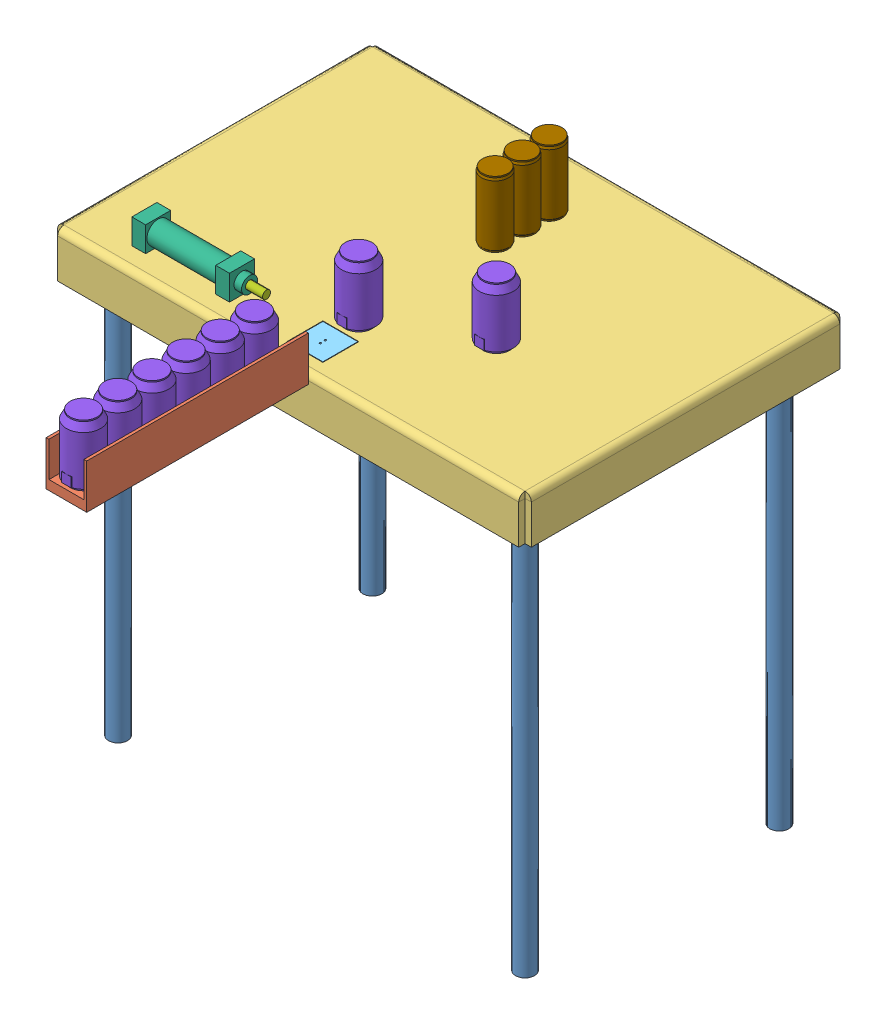
SolidWorks assembly Full_Assembly_v4, configuration Default. Lengths in mm.
Overall size (946.15 1065.21 1084.08).
19 component instances, 9 part files, 57 mates.
Components (placement in the parent):
- M37 Metal Table-1: M37 Metal Table [Default] at (-122.75 340.8931 1031.9817) size (914.4 863.6 609.6)
- Goose Output-1: Goose Output [Default] at (293.9688 417.0931 1047.8567) size (80.96 88.9 442.73)
- Table Topper-1: Table Topper [Default] at (-125.925 345.3431 1035.1567) size (946.15 90.8 641.35)
- Load Cell Assembly-1: Load Cell Assembly [Default] at (309.0555 378.227 899.7114) size (69.85 26.2 103.99)
  - Load Cell and Brace-1: Load Cell and Brace [Default] at (-9.1055 31.7162 92.7424) size (69 14.2 83)
  - scalePlate_v2_234-1: scalePlate_v2_234 [Default] at (-9.5305 57.9162 113.7283) x (0 0 -1) z (-1 0 0) size (69.85 12 69.85)
- Cylinder-1: Cylinder [Default] at (-22.0508 486.1431 953.5147) x (0 0 1) z (1 0 0) size (50 50 210)
- Rod-1: Rod [Default] at (221.9492 461.1431 978.5147) x (0 0.637822 -0.770184) z (0 0.770184 0.637822) size (16 134 16)
- can355mL-1: can355mL [Default] at (334.45 436.1431 1115.1477) x (0 0 -1) z (1 0 0) size (68.26 122.24 68.26)
- can355mL-2: can355mL [Default] at (334.45 436.1431 1251.6727) x (0 0 -1) z (1 0 0) size (68.26 122.24 68.26)
- can355mL-3: can355mL [Default] at (334.45 436.1431 1183.4102) x (0 0 -1) z (1 0 0) size (68.26 122.24 68.26)
- can250mL-1: can250mL [Default] at (334.45 436.1431 634.4892) x (0.234731 0 0.97206) z (-0.97206 0 0.234731) size (53.98 131.76 53.98)
- can250mL-2: can250mL [Default] at (334.45 436.1431 580.5142) x (0.907124 0 -0.420864) z (0.420864 0 0.907124) size (53.98 131.76 53.98)
- can250mL-3: can250mL [Default] at (334.45 436.1431 526.5392) x (0.515444 0 0.856923) z (-0.856923 0 0.515444) size (53.98 131.76 53.98)
- can355mL-7: can355mL [Default] at (334.45 436.1431 907.006) x (0 0 -1) z (1 0 0) size (68.26 122.24 68.26)
- can355mL-8: can355mL [Default] at (334.45 436.1431 1456.4602) x (0 0 -1) z (1 0 0) size (68.26 122.24 68.26)
- can355mL-9: can355mL [Default] at (334.45 436.1431 1319.9352) x (0 0 -1) z (1 0 0) size (68.26 122.24 68.26)
- can355mL-10: can355mL [Default] at (334.45 436.1431 1388.1977) x (0 0 -1) z (1 0 0) size (68.26 122.24 68.26)
- can355mL-11: can355mL [Default] at (509.2982 436.1431 806.848) x (0 0 -1) z (1 0 0) size (68.26 122.24 68.26)
Mates (geometry in assembly coordinates):
- Width1: width aligned: plane of M37 Metal Table-1 through (791.65 366.2931 1031.9817) normal (1 0 0); plane of Table Topper-1 through (-122.75 366.2931 1031.9817) normal (-1 0 0); plane of M37 Metal Table-1 through (807.525 423.4431 1035.1567) normal (1 0 0); plane of Table Topper-1 through (-138.625 423.4431 1035.1567) normal (-1 0 0)
- Width2: width aligned: plane of M37 Metal Table-1 through (-122.75 366.2931 1031.9817) normal (0 0 1); plane of Table Topper-1 through (-122.75 366.2931 422.3817) normal (0 0 -1); plane of M37 Metal Table-1 through (-125.925 423.4431 1047.8567) normal (0 0 1); plane of Table Topper-1 through (-125.925 423.4431 406.5067) normal (0 0 -1)
- Distance1: distance = 863.6 mm aligned: plane of M37 Metal Table-1 through (-122.75 -446.5069 1031.9817) normal (0 -1 0); plane of Goose Output-1 through (374.9313 417.0931 1490.5914) normal (0 -1 0)
- LimitDistance1: limit distance = 432.5938 mm aligned: plane of Goose Output-1 through (374.9313 505.9931 1490.5914) normal (1 0 0); plane of Table Topper-1 through (807.525 423.4431 1035.1567) normal (1 0 0)
- LimitDistance2: limit distance = 432.5938 mm aligned: plane of Table Topper-1 through (-138.625 423.4431 1035.1567) normal (-1 0 0); plane of Goose Output-1 through (293.9688 417.0931 1490.5914) normal (-1 0 0)
- Parallel1: parallel aligned: plane of Goose Output-1 through (299.525 436.1431 1490.5914) normal (0 1 0); plane of Table Topper-1 through (-125.925 436.1431 1035.1567) normal (0 1 0)
- Coincident5: coincident aligned: plane of Goose Output-1 through (299.525 436.1431 1490.5914) normal (0 1 0); plane of Table Topper-1 through (-125.925 436.1431 1035.1567) normal (0 1 0)
- Coincident7: coincident aligned: plane of Table Topper-1 through (-125.925 436.1431 1035.1567) normal (0 1 0); plane of Load Cell Assembly-1/scalePlate_v2_234-1 through (299.525 436.1431 1013.4397) normal (0 1 0)
- Concentric1: concentric anti-aligned: cylinder of Cylinder-1 through (187.9492 461.1431 978.5147) axis (-1 0 0) radius 16; cylinder of Rod-1 through (87.9492 461.1431 978.5147) axis (1 0 0) radius 8
- LimitDistance3: limit distance = 34 mm aligned: plane of Rod-1 through (221.9492 461.1431 978.5147) normal (1 0 0); plane of Cylinder-1 through (187.9492 461.1431 978.5147) normal (1 0 0)
- Parallel2: parallel anti-aligned: plane of Table Topper-1 through (-125.925 423.4431 1047.8567) normal (0 0 1); plane of Cylinder-1 through (172.9492 486.1431 953.5147) normal (0 0 -1)
- Coincident9: coincident anti-aligned: plane of Table Topper-1 through (-125.925 436.1431 1035.1567) normal (0 1 0); plane of Cylinder-1 through (5.4492 436.1431 953.5147) normal (0 -1 0)
- Width3: width anti-aligned: plane of Goose Output-1 through (374.9313 505.9931 1490.5914) normal (1 0 0); plane of Load Cell Assembly-1/scalePlate_v2_234-1 through (293.9688 417.0931 1490.5914) normal (-1 0 0); plane of Goose Output-1 through (299.525 432.1431 1013.4397) normal (-1 0 0); plane of Load Cell Assembly-1/scalePlate_v2_234-1 through (369.375 432.1431 1013.4397) normal (1 0 0)
- Width4: width anti-aligned: plane of Cylinder-1 through (172.9492 486.1431 953.5147) normal (0 0 -1); plane of Load Cell Assembly-1/scalePlate_v2_234-1 through (172.9492 486.1431 1003.5147) normal (0 0 1); plane of Cylinder-1 through (299.525 432.1431 1013.4397) normal (0 0 1); plane of Load Cell Assembly-1/scalePlate_v2_234-1 through (299.525 432.1431 943.5897) normal (0 0 -1)
- Width5: width anti-aligned: plane of Table Topper-1 through (807.525 423.4431 1035.1567) normal (1 0 0); plane of Load Cell Assembly-1/scalePlate_v2_234-1 through (-138.625 423.4431 1035.1567) normal (-1 0 0); plane of Table Topper-1 through (299.525 432.1431 1013.4397) normal (-1 0 0); plane of Load Cell Assembly-1/scalePlate_v2_234-1 through (369.375 432.1431 1013.4397) normal (1 0 0)
- Coincident11: coincident anti-aligned: plane of Table Topper-1 through (-125.925 436.1431 1035.1567) normal (0 1 0); plane of can250mL-1 through (340.4122 436.1431 659.1796) normal (0 -1 0)
- Coincident18: coincident anti-aligned: plane of Table Topper-1 through (-125.925 436.1431 1035.1567) normal (0 1 0); plane of can355mL-2 through (334.45 436.1431 1224.6852) normal (0 -1 0)
- Coincident19: coincident anti-aligned: plane of Table Topper-1 through (-125.925 436.1431 1035.1567) normal (0 1 0); plane of can355mL-3 through (334.45 436.1431 1156.4227) normal (0 -1 0)
- Tangent5: tangent anti-aligned: cylinder of can355mL-2 through (334.45 436.1431 1251.6727) axis (0 -1 0) radius 34.1313; cylinder of can355mL-3 through (334.45 436.1431 1183.4102) axis (0 -1 0) radius 34.1313
- Width6: width: plane of Goose Output-1 through (299.525 505.9931 1490.5914) normal (1 0 0); plane of can250mL-1 through (369.375 436.1431 1490.5914) normal (-1 0 0); cylinder of Goose Output-1 through (334.45 436.1431 634.4892) axis (0 -1 0) radius 26.9875
- Width8: width: plane of Goose Output-1 through (369.375 436.1431 1490.5914) normal (-1 0 0); plane of can355mL-2 through (299.525 505.9931 1490.5914) normal (1 0 0); cylinder of Goose Output-1 through (334.45 436.1431 1251.6727) axis (0 -1 0) radius 34.1313
- Width10: width: plane of Goose Output-1 through (299.525 505.9931 1490.5914) normal (1 0 0); plane of can355mL-3 through (369.375 436.1431 1490.5914) normal (-1 0 0); cylinder of Goose Output-1 through (334.45 436.1431 1183.4102) axis (0 -1 0) radius 34.1313
- Coincident20: coincident anti-aligned: plane of Table Topper-1 through (-125.925 436.1431 1035.1567) normal (0 1 0); plane of can250mL-2 through (357.491 436.1431 569.8243) normal (0 -1 0)
- Coincident21: coincident anti-aligned: plane of Table Topper-1 through (-125.925 436.1431 1035.1567) normal (0 1 0); plane of can250mL-3 through (347.5423 436.1431 548.3051) normal (0 -1 0)
- Tangent6: tangent anti-aligned: cylinder of can250mL-1 through (334.45 436.1431 634.4892) axis (0 -1 0) radius 26.9875; cylinder of can250mL-2 through (334.45 436.1431 580.5142) axis (0 -1 0) radius 26.9875
- Tangent7: tangent anti-aligned: cylinder of can250mL-2 through (334.45 436.1431 580.5142) axis (0 -1 0) radius 26.9875; cylinder of can250mL-3 through (334.45 436.1431 526.5392) axis (0 -1 0) radius 26.9875
- Width11: width: plane of Goose Output-1 through (299.525 505.9931 1490.5914) normal (1 0 0); plane of can250mL-2 through (369.375 436.1431 1490.5914) normal (-1 0 0); cylinder of Goose Output-1 through (334.45 436.1431 580.5142) axis (0 -1 0) radius 26.9875
- Width12: width: plane of Goose Output-1 through (299.525 505.9931 1490.5914) normal (1 0 0); plane of can250mL-3 through (369.375 436.1431 1490.5914) normal (-1 0 0); cylinder of Goose Output-1 through (334.45 436.1431 526.5392) axis (0 -1 0) radius 26.9875
- Coincident22: coincident anti-aligned: plane of Goose Output-1 through (293.9688 417.0931 1047.8567) normal (0 0 -1); plane of Table Topper-1 through (-125.925 423.4431 1047.8567) normal (0 0 1)
- Width14: width aligned: plane of Table Topper-1 through (370.391 345.3431 1014.4557) normal (-1 0 0); plane of Table Topper-1 through (298.509 345.3431 1014.4557) normal (1 0 0); plane of Load Cell Assembly-1/scalePlate_v2_234-1 through (299.525 432.1431 1013.4397) normal (-1 0 0); plane of Load Cell Assembly-1/scalePlate_v2_234-1 through (369.375 432.1431 1013.4397) normal (1 0 0)
- Width15: width anti-aligned: plane of Table Topper-1 through (298.509 345.3431 1014.4557) normal (0 0 -1); plane of Table Topper-1 through (298.509 345.3431 942.5737) normal (0 0 1); plane of Load Cell Assembly-1/scalePlate_v2_234-1 through (299.525 432.1431 1013.4397) normal (0 0 1); plane of Load Cell Assembly-1/scalePlate_v2_234-1 through (299.525 432.1431 943.5897) normal (0 0 -1)
- Width17: width: plane of Goose Output-1 through (369.375 436.1431 1490.5914) normal (-1 0 0); plane of Goose Output-1 through (299.525 505.9931 1490.5914) normal (1 0 0); cylinder of can355mL-4 through (334.45 436.1431 1259.8293) axis (0 -1 0) radius 34.1313
- Coincident31: coincident anti-aligned: plane of Table Topper-1 through (-125.925 436.1431 1035.1567) normal (0 1 0); plane of can355mL-7 through (334.45 436.1431 880.0185) normal (0 -1 0)
- Width19: width: plane of Goose Output-1 through (369.375 436.1431 1490.5914) normal (-1 0 0); plane of Goose Output-1 through (299.525 505.9931 1490.5914) normal (1 0 0); cylinder of can355mL-7 through (334.45 436.1431 907.006) axis (0 -1 0) radius 34.1313
- Coincident33: coincident anti-aligned: plane of Table Topper-1 through (-125.925 436.1431 1035.1567) normal (0 1 0); plane of can355mL-1 through (334.45 436.1431 1088.1602) normal (0 -1 0)
- Tangent13: tangent anti-aligned: cylinder of can355mL-1 through (334.45 436.1431 1115.1477) axis (0 -1 0) radius 34.1313; cylinder of can355mL-3 through (334.45 436.1431 1183.4102) axis (0 -1 0) radius 34.1313
- Width20: width: plane of Goose Output-1 through (299.525 505.9931 1490.5914) normal (1 0 0); plane of Goose Output-1 through (369.375 436.1431 1490.5914) normal (-1 0 0); cylinder of can355mL-1 through (334.45 436.1431 1115.1477) axis (0 -1 0) radius 34.1313
- Parallel4: parallel aligned: plane of M37 Metal Table-1 through (-122.75 366.2931 1031.9817) normal (0 0 1); plane of can355mL-7 through (334.45 436.1431 941.1373) normal (0 0 1)
- Parallel5: parallel aligned: plane of M37 Metal Table-1 through (-122.75 366.2931 1031.9817) normal (0 0 1); plane of can355mL-2 through (334.45 436.1431 1285.8039) normal (0 0 1)
- Parallel6: parallel aligned: plane of M37 Metal Table-1 through (-122.75 366.2931 1031.9817) normal (0 0 1); plane of can355mL-3 through (334.45 436.1431 1217.5414) normal (0 0 1)
- Parallel7: parallel aligned: plane of M37 Metal Table-1 through (-122.75 366.2931 1031.9817) normal (0 0 1); plane of can355mL-1 through (334.45 436.1431 1149.2789) normal (0 0 1)
- LimitDistance14: limit distance = 208.1417 mm aligned: plane of can355mL-7 through (334.45 436.1431 941.1373) normal (0 0 1); plane of can355mL-1 through (334.45 436.1431 1149.2789) normal (0 0 1)
- Tangent14: tangent anti-aligned: cylinder of can355mL-9 through (334.45 436.1431 1319.9352) axis (0 -1 0) radius 34.1313; cylinder of can355mL-10 through (334.45 436.1431 1388.1977) axis (0 -1 0) radius 34.1313
- Tangent15: tangent anti-aligned: cylinder of can355mL-8 through (334.45 436.1431 1456.4602) axis (0 -1 0) radius 34.1313; cylinder of can355mL-10 through (334.45 436.1431 1388.1977) axis (0 -1 0) radius 34.1313
- Coincident38: coincident anti-aligned: plane of Table Topper-1 through (-125.925 436.1431 1035.1567) normal (0 1 0); plane of can355mL-8 through (334.45 436.1431 1429.4727) normal (0 -1 0)
- Coincident39: coincident aligned: plane of can355mL-9 through (334.45 436.1431 1292.9477) normal (0 -1 0); plane of can355mL-10 through (334.45 436.1431 1361.2102) normal (0 -1 0)
- Coincident40: coincident anti-aligned: plane of Table Topper-1 through (-125.925 436.1431 1035.1567) normal (0 1 0); plane of can355mL-10 through (334.45 436.1431 1361.2102) normal (0 -1 0)
- Width21: width: plane of Goose Output-1 through (299.525 505.9931 1490.5914) normal (1 0 0); plane of can355mL-8 through (369.375 436.1431 1490.5914) normal (-1 0 0); cylinder of Goose Output-1 through (334.45 436.1431 1456.4602) axis (0 -1 0) radius 34.1313
- Width22: width: plane of Goose Output-1 through (374.9313 505.9931 1490.5914) normal (1 0 0); plane of can355mL-10 through (293.9688 417.0931 1490.5914) normal (-1 0 0); cylinder of Goose Output-1 through (334.45 436.1431 1388.1977) axis (0 -1 0) radius 34.1313
- Width23: width: plane of Goose Output-1 through (374.9313 505.9931 1490.5914) normal (1 0 0); plane of can355mL-9 through (293.9688 417.0931 1490.5914) normal (-1 0 0); cylinder of Goose Output-1 through (334.45 436.1431 1319.9352) axis (0 -1 0) radius 34.1313
- LimitDistance15: limit distance = 68.2625 mm aligned: plane of can355mL-9 through (334.45 436.1431 1354.0664) normal (0 0 1); plane of can355mL-2 through (334.45 436.1431 1285.8039) normal (0 0 1)
- Parallel8: parallel aligned: plane of M37 Metal Table-1 through (-122.75 366.2931 1031.9817) normal (0 0 1); plane of can355mL-8 through (334.45 436.1431 1490.5914) normal (0 0 1)
- Parallel10: parallel aligned: plane of M37 Metal Table-1 through (-122.75 366.2931 1031.9817) normal (0 0 1); plane of can355mL-10 through (334.45 436.1431 1422.3289) normal (0 0 1)
- LimitDistance16: limit distance = 0 mm aligned: plane of can355mL-8 through (334.45 436.1431 1490.5914) normal (0 0 1); plane of Goose Output-1 through (293.9688 417.0931 1490.5914) normal (0 0 1)
- Coincident44: coincident anti-aligned: plane of Table Topper-1 through (-125.925 436.1431 1035.1567) normal (0 1 0); plane of can355mL-11 through (509.2982 436.1431 779.8605) normal (0 -1 0)
- Parallel12: parallel aligned: plane of M37 Metal Table-1 through (-122.75 366.2931 1031.9817) normal (0 0 1); plane of can355mL-11 through (509.2982 436.1431 840.9792) normal (0 0 1)
- LimitDistance18: limit distance = 100.158 mm aligned: plane of can355mL-11 through (509.2982 436.1431 840.9792) normal (0 0 1); plane of can355mL-7 through (334.45 436.1431 941.1373) normal (0 0 1)
